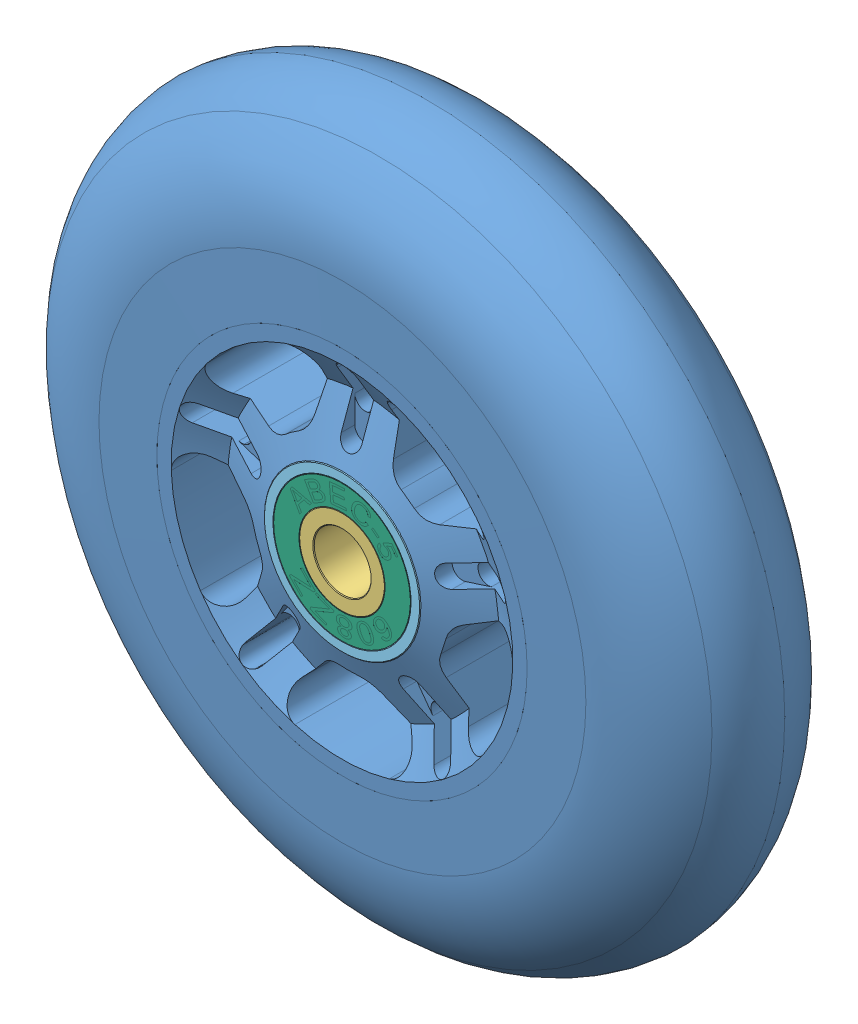
SolidWorks assembly 100mm Scooter Wheel, configuration Default. Lengths in mm.
Overall size (100 100 24.4).
36 component instances, 6 part files, 12 mates.
Components (placement in the parent):
- 100mm Scooter Wheel-1: 100mm Scooter Wheel [Default] at (55.2423 52.5251 67.0743) size (100 100 24.4)
- 8mm Bearing Spacer-1: 8mm Bearing Spacer [Default] at (55.2423 52.5251 72.2743) x (0 0 -1) z (0.991115 0.133008 0) size (10.4 12.1 12.1)
- ABEC-5 608ZZ Bearing-3: ABEC-5 608ZZ Bearing [Default] at (49.1248 46.4687 67.156) size (27.07 27.07 7)
  - ABEC-5 608ZZ Inner Race-1: ABEC-5 608ZZ Inner Race [Default] at (6.1175 6.0564 8.6183) size (12.1 12.1 7)
  - Ball Bearing 3.969 mm-1: Ball Bearing 3.969 mm [Default] at (13.9421 6.0697 8.5936) x (0.058889 0.681223 0.729703) z (0.042701 -0.732022 0.679942) size (3.97 3.97 3.97)
  - ABEC-5 608ZZ Outer Race-1: ABEC-5 608ZZ Outer Race [Default] at (6.1175 6.0564 8.6183) x (0.129165 -0.991623 0) z (0 0 1) size (22 22 7)
  - Ball Bearing 3.969 mm-2: Ball Bearing 3.969 mm [Default] at (12.8872 9.9802 8.5936) x (-0.289612 0.619401 0.729703) z (0.402991 -0.612599 0.679942) size (3.97 3.97 3.97)
  - Ball Bearing 3.969 mm-3: Ball Bearing 3.969 mm [Default] at (10.0183 12.8394 8.5936) x (-0.560512 0.391611 0.729703) z (0.6553 -0.329031 0.679942) size (3.97 3.97 3.97)
  - Ball Bearing 3.969 mm-4: Ball Bearing 3.969 mm [Default] at (6.1042 13.881 8.5936) x (-0.681223 0.058889 0.729703) z (0.732022 0.042701 0.679942) size (3.97 3.97 3.97)
  - Ball Bearing 3.969 mm-5: Ball Bearing 3.969 mm [Default] at (2.1937 12.8261 8.5936) x (-0.619401 -0.289612 0.729703) z (0.612599 0.402991 0.679942) size (3.97 3.97 3.97)
  - Ball Bearing 3.969 mm-6: Ball Bearing 3.969 mm [Default] at (-0.6655 9.9572 8.5936) x (-0.391611 -0.560512 0.729703) z (0.329031 0.6553 0.679942) size (3.97 3.97 3.97)
  - Ball Bearing 3.969 mm-7: Ball Bearing 3.969 mm [Default] at (-1.7071 6.0431 8.5936) x (-0.058889 -0.681223 0.729703) z (-0.042701 0.732022 0.679942) size (3.97 3.97 3.97)
  - Ball Bearing 3.969 mm-8: Ball Bearing 3.969 mm [Default] at (-0.6522 2.1326 8.5936) x (0.289612 -0.619401 0.729703) z (-0.402991 0.612599 0.679942) size (3.97 3.97 3.97)
  - Ball Bearing 3.969 mm-9: Ball Bearing 3.969 mm [Default] at (2.2167 -0.7266 8.5936) x (0.560512 -0.391611 0.729703) z (-0.6553 0.329031 0.679942) size (3.97 3.97 3.97)
  - Ball Bearing 3.969 mm-10: Ball Bearing 3.969 mm [Default] at (6.1308 -1.7682 8.5936) x (0.681223 -0.058889 0.729703) z (-0.732022 -0.042701 0.679942) size (3.97 3.97 3.97)
  - Ball Bearing 3.969 mm-11: Ball Bearing 3.969 mm [Default] at (10.0413 -0.7133 8.5936) x (0.619401 0.289612 0.729703) z (-0.612599 -0.402991 0.679942) size (3.97 3.97 3.97)
  - Ball Bearing 3.969 mm-12: Ball Bearing 3.969 mm [Default] at (12.9005 2.1556 8.5936) x (0.391611 0.560512 0.729703) z (-0.329031 -0.6553 0.679942) size (3.97 3.97 3.97)
  - ABEC-5 608ZZ Bearing Sheild-1: ABEC-5 608ZZ Bearing Sheild [Default] at (6.1175 6.0564 6.1183) x (0 0 -1) z (0.760544 -0.649286 0) size (1 19.2 19.2)
  - ABEC-5 608ZZ Bearing Sheild-2: ABEC-5 608ZZ Bearing Sheild [Default] at (6.1175 6.0564 11.1183) x (0 0 1) z (-1 0 0) size (1 19.2 19.2)
- ABEC-5 608ZZ Bearing-4: ABEC-5 608ZZ Bearing [Default] at (49.1248 46.4687 49.756) size (27.07 27.07 7)
  - ABEC-5 608ZZ Inner Race-1: ABEC-5 608ZZ Inner Race [Default] at (6.1175 6.0564 8.6183) size (12.1 12.1 7)
  - Ball Bearing 3.969 mm-1: Ball Bearing 3.969 mm [Default] at (13.9421 6.0697 8.5936) x (0.058889 0.681223 0.729703) z (0.042701 -0.732022 0.679942) size (3.97 3.97 3.97)
  - ABEC-5 608ZZ Outer Race-1: ABEC-5 608ZZ Outer Race [Default] at (6.1175 6.0564 8.6183) x (0.129165 -0.991623 0) z (0 0 1) size (22 22 7)
  - Ball Bearing 3.969 mm-2: Ball Bearing 3.969 mm [Default] at (12.8872 9.9802 8.5936) x (-0.289612 0.619401 0.729703) z (0.402991 -0.612599 0.679942) size (3.97 3.97 3.97)
  - Ball Bearing 3.969 mm-3: Ball Bearing 3.969 mm [Default] at (10.0183 12.8394 8.5936) x (-0.560512 0.391611 0.729703) z (0.6553 -0.329031 0.679942) size (3.97 3.97 3.97)
  - Ball Bearing 3.969 mm-4: Ball Bearing 3.969 mm [Default] at (6.1042 13.881 8.5936) x (-0.681223 0.058889 0.729703) z (0.732022 0.042701 0.679942) size (3.97 3.97 3.97)
  - Ball Bearing 3.969 mm-5: Ball Bearing 3.969 mm [Default] at (2.1937 12.8261 8.5936) x (-0.619401 -0.289612 0.729703) z (0.612599 0.402991 0.679942) size (3.97 3.97 3.97)
  - Ball Bearing 3.969 mm-6: Ball Bearing 3.969 mm [Default] at (-0.6655 9.9572 8.5936) x (-0.391611 -0.560512 0.729703) z (0.329031 0.6553 0.679942) size (3.97 3.97 3.97)
  - Ball Bearing 3.969 mm-7: Ball Bearing 3.969 mm [Default] at (-1.7071 6.0431 8.5936) x (-0.058889 -0.681223 0.729703) z (-0.042701 0.732022 0.679942) size (3.97 3.97 3.97)
  - Ball Bearing 3.969 mm-8: Ball Bearing 3.969 mm [Default] at (-0.6522 2.1326 8.5936) x (0.289612 -0.619401 0.729703) z (-0.402991 0.612599 0.679942) size (3.97 3.97 3.97)
  - Ball Bearing 3.969 mm-9: Ball Bearing 3.969 mm [Default] at (2.2167 -0.7266 8.5936) x (0.560512 -0.391611 0.729703) z (-0.6553 0.329031 0.679942) size (3.97 3.97 3.97)
  - Ball Bearing 3.969 mm-10: Ball Bearing 3.969 mm [Default] at (6.1308 -1.7682 8.5936) x (0.681223 -0.058889 0.729703) z (-0.732022 -0.042701 0.679942) size (3.97 3.97 3.97)
  - Ball Bearing 3.969 mm-11: Ball Bearing 3.969 mm [Default] at (10.0413 -0.7133 8.5936) x (0.619401 0.289612 0.729703) z (-0.612599 -0.402991 0.679942) size (3.97 3.97 3.97)
  - Ball Bearing 3.969 mm-12: Ball Bearing 3.969 mm [Default] at (12.9005 2.1556 8.5936) x (0.391611 0.560512 0.729703) z (-0.329031 -0.6553 0.679942) size (3.97 3.97 3.97)
  - ABEC-5 608ZZ Bearing Sheild-1: ABEC-5 608ZZ Bearing Sheild [Default] at (6.1175 6.0564 6.1183) x (0 0 -1) z (0.760544 -0.649286 0) size (1 19.2 19.2)
  - ABEC-5 608ZZ Bearing Sheild-2: ABEC-5 608ZZ Bearing Sheild [Default] at (6.1175 6.0564 11.1183) x (0 0 1) z (-1 0 0) size (1 19.2 19.2)
Mates (geometry in assembly coordinates):
- Concentric1: concentric aligned: cylinder of 100mm Scooter Wheel-1 through (55.2423 52.5251 53.5743) axis (0 0 1) radius 10.65; cylinder of ABEC-5 608ZZ Bearing-3/ABEC-5 608ZZ Inner Race-1 through (55.2423 52.5251 79.1348) axis (0 0 1) radius 11
- Coincident1: coincident aligned: plane of 100mm Scooter Wheel-1 through (55.2423 63.2751 79.2743) normal (0 0 1); plane of ABEC-5 608ZZ Bearing-3/ABEC-5 608ZZ Inner Race-1 through (55.2423 62.1251 79.2743) normal (0 0 1)
- Concentric2: concentric aligned: cylinder of 100mm Scooter Wheel-1 through (55.2423 52.5251 53.5743) axis (0 0 1) radius 10.65; cylinder of ? through (55.2423 52.5251 -5.218) axis (0 0 1) radius 11
- Concentric3: concentric aligned: cylinder of ? through (55.2423 52.5251 -5.218) axis (0 0 1) radius 4; cylinder of 8mm Bearing Spacer-1 through (55.2423 52.5251 -5.0785) axis (0 0 1) radius 4
- Coincident2: coincident anti-aligned: plane of ? through (55.002 56.5179 61.8743) normal (0 0 1); plane of 8mm Bearing Spacer-1 through (55.2423 52.5251 61.8743) normal (0 0 -1)
- Coincident3: coincident anti-aligned: plane of ABEC-5 608ZZ Bearing-3/ABEC-5 608ZZ Inner Race-1 through (55.2423 58.5751 72.2743) normal (0 0 -1); plane of 8mm Bearing Spacer-1 through (55.2423 52.5251 72.2743) normal (0 0 1)
- Concentric4: concentric aligned: cylinder of 8mm Bearing Spacer-1 through (55.2423 52.5251 61.8743) axis (0 0 1) radius 4; cylinder of ABEC-5 608ZZ Bearing-3/ABEC-5 608ZZ Inner Race-1 through (55.2423 52.5251 79.1348) axis (0 0 1) radius 4
- Coincident4: coincident anti-aligned: plane of 8mm Bearing Spacer-1 through (55.2423 52.5251 72.2743) normal (0 0 1); plane of ABEC-5 608ZZ Bearing-3/ABEC-5 608ZZ Inner Race-1 through (55.2423 58.5751 72.2743) normal (0 0 -1)
- Concentric5: concentric aligned: cylinder of 100mm Scooter Wheel-1 through (55.2423 52.5251 53.5743) axis (0 0 1) radius 11; cylinder of ABEC-5 608ZZ Bearing-3/ABEC-5 608ZZ Outer Race-1 through (55.2423 52.5251 79.1348) axis (0 0 1) radius 11
- Coincident5: coincident aligned: plane of 100mm Scooter Wheel-1 through (55.2423 78.5251 79.2743) normal (0 0 1); plane of ABEC-5 608ZZ Bearing-3/ABEC-5 608ZZ Outer Race-1 through (64.7619 53.7651 79.2743) normal (0 0 1)
- Concentric6: concentric aligned: cylinder of 8mm Bearing Spacer-1 through (55.2423 52.5251 61.8743) axis (0 0 1) radius 4; cylinder of ABEC-5 608ZZ Bearing-4/ABEC-5 608ZZ Inner Race-1 through (55.2423 52.5251 61.7348) axis (0 0 1) radius 4
- Coincident6: coincident aligned: plane of 100mm Scooter Wheel-1 through (55.2423 78.5251 54.8743) normal (0 0 -1); plane of ABEC-5 608ZZ Bearing-4/ABEC-5 608ZZ Inner Race-1 through (55.2423 58.5751 54.8743) normal (0 0 -1)
